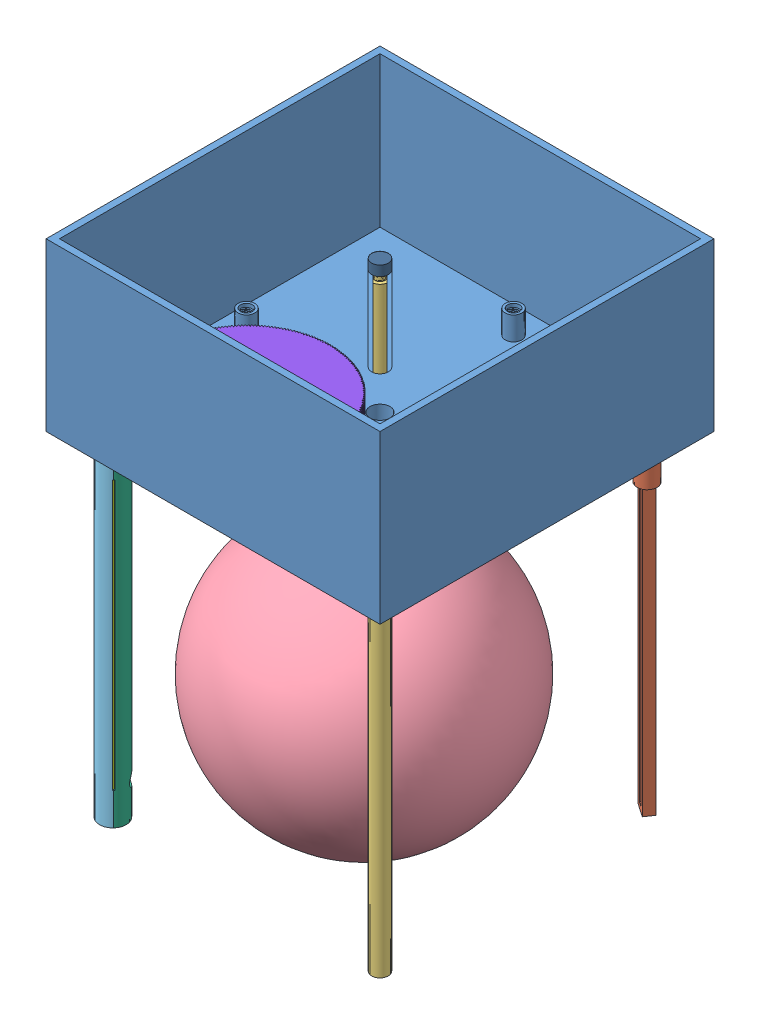
SolidWorks assembly Taşıyıcı kuşak, configuration Varsayılan. Lengths in mm.
Overall size (102.12 154.23 102.12).
15 component instances, 11 part files, 26 mates.
Components (placement in the parent):
- gövde-1: gövde [Varsayılan] at (-14.3626 -37.2025 100) size (100 50 100)
- kuşak desteği-1: kuşak desteği [Varsayılan] at (26.8448 -135.2025 62.6537) x (-0.823429 0 -0.56742) z (0.56742 0 -0.823429) size (6 100 6)
- yardımcı ayak-1: yardımcı ayak [Varsayılan] at (-55.6722 -137.2025 57.9647) x (0.546904 0 0.837196) z (-0.837196 0 0.546904) size (5 102 5)
- yardımcı ayak-2: yardımcı ayak [Varsayılan] at (23.2198 -137.2025 140.7026) x (0.956564 0 -0.291524) z (0.291524 0 0.956564) size (5 102 5)
- drone küresi-1: drone küresi [Varsayılan] at (-18.2063 -101.4294 100.9507) size (80 80 80)
- Montaj2 kusak sıkıştırıcısı-1: Montaj2 kusak sıkıştırıcısı [Varsayılan] at (-90.3425 -98.3272 238.512) x (0.733876 0 0.679283) z (-0.679283 0 0.733876) size (8 103 8)
  - kuşak sıkıştırıcısı 1.yarı-1: kuşak sıkıştırıcısı 1.yarı [Default] at (-40.5128 -38.8753 -96.7362) size (8 103 6)
  - kuşak sıkıştırıcısı 2.yarı-1: kuşak sıkıştırıcısı 2.yarı [Default] at (-40.5128 -38.8753 -96.7362) size (8 103 4)
  - kuşak tutucu-1: kuşak tutucu [Varsayılan] at (-37.5128 -30.8753 -96.7362) x (-0.818094 0 0.575085) z (-0.575085 0 -0.818094) size (1 84 1)
  - kuşak tutucu-2: kuşak tutucu [Varsayılan] at (-43.5128 -30.8753 -96.7362) x (0.97773 0 0.209869) z (-0.209869 0 0.97773) size (1 84 1)
- tetikleyici dişli-1: tetikleyici dişli [Varsayılan] at (-34.2101 -32.2025 119.8475) x (0.932244 0 0.36183) z (-0.36183 0 0.932244) size (49.88 5 49.88)
- tutucu civatası-1: tutucu civatası [Varsayılan] at (-54.3626 -32.2025 140) x (0.951302 0 0.30826) z (-0.30826 0 0.951302) size (7 15.23 6.99)
- yardımcı ayak civatası-1: yardımcı ayak civatası [Varsayılan] at (-54.3049 -32.2025 60.0577) x (-0.034485 0 -0.999405) z (-0.999405 0 0.034485) size (5 8.18 5)
- yardımcı ayak civatası-2: yardımcı ayak civatası [Varsayılan] at (25.6112 -32.2025 139.9738) x (0.995898 0 -0.090486) z (-0.090486 0 -0.995898) size (5 8.18 5)
- kuşak destegi civatası-1: kuşak destegi civatası [Varsayılan] at (25.6374 -32.2025 60) x (-0.844828 0 0.535038) z (0.535038 0 0.844828) size (9.99 17.36 8.86)
Mates (geometry in assembly coordinates):
- Teğet1: tangent anti-aligned: plane of gövde-1 through (-13.3019 -35.2025 98.9393) normal (-0.707107 0 0.707107); cylinder of yardımcı ayak-1 through (-54.3049 -145.7321 60.0577) axis (0 -1 0) radius 1.5
- Çakışık1: coincident aligned: plane of gövde-1 through (-14.3626 -35.2025 100) normal (0 1 0); plane of yardımcı ayak-1 through (-55.1253 -35.2025 58.8019) normal (0 1 0)
- Çakışık2: coincident aligned: plane of gövde-1 through (-14.3626 -35.2025 100) normal (0 1 0); plane of yardımcı ayak-2 through (24.1763 -35.2025 140.4111) normal (0 1 0)
- Teğet4: tangent anti-aligned: plane of gövde-1 through (-15.4233 -35.2025 101.0607) normal (0.707107 0 -0.707107); cylinder of yardımcı ayak-2 through (25.6112 -145.7321 139.9738) axis (0 -1 0) radius 1.5
- Çakışık6: coincident aligned: plane of gövde-1 through (-14.3626 -35.2025 100) normal (0 1 0); plane of kuşak desteği-1 through (25.6374 -35.2025 60) normal (0 1 0)
- Çakışık7: coincident aligned: circle of gövde-1; circle of kuşak desteği-1
- Uzaklığı Sınırla7: limit distance = 36.9629 mm: cylinder of yardımcı ayak-2 through (25.6112 -145.7321 139.9738) axis (0 -1 0) radius 1.5; cylinder of gövde-1 through (-2.6469 -35.2025 111.7157) axis (0 -1 0) radius 1.5
- Uzaklığı Sınırla4: limit distance = 0.0371 mm: cylinder of yardımcı ayak-2 through (25.6112 -145.7321 139.9738) axis (0 -1 0) radius 1.5; cylinder of gövde-1 through (25.6374 -35.2025 140) axis (0 -1 0) radius 1.5
- Uzaklığı Sınırla5: limit distance = 0.0816 mm: cylinder of yardımcı ayak-1 through (-54.3049 -145.7321 60.0577) axis (0 -1 0) radius 1.5; cylinder of gövde-1 through (-54.3626 -35.2025 60) axis (0 -1 0) radius 1.5
- Uzaklığı Sınırla6: limit distance = 36.9184 mm: cylinder of yardımcı ayak-1 through (-54.3049 -145.7321 60.0577) axis (0 -1 0) radius 1.5; cylinder of gövde-1 through (-26.0783 -35.2025 88.2843) axis (0 -1 0) radius 1.5
- Eş Merkezli1: concentric aligned: cylinder of gövde-1 through (-54.3626 -35.2025 140) axis (0 -1 0) radius 3; cylinder of Montaj2 kusak sıkıştırıcısı-1/kuşak sıkıştırıcısı 1.yarı-1 through (-54.3626 -34.2025 140) axis (0 -1 0) radius 3
- Çakışık8: coincident anti-aligned: plane of gövde-1 through (-14.3626 -37.2025 100) normal (0 -1 0); plane of Montaj2 kusak sıkıştırıcısı-1/kuşak sıkıştırıcısı 1.yarı-1 through (-54.3626 -37.2025 140) normal (0 1 0)
- Çakışık9: coincident anti-aligned: plane of gövde-1 through (-14.3626 -32.2025 100) normal (0 1 0); plane of tetikleyici dişli-1 through (-34.2101 -32.2025 119.8475) normal (0 -1 0)
- Eş Merkezli4: concentric aligned: cylinder of gövde-1 through (-54.3626 -34.2025 140) axis (0 1 0) radius 2.5; cylinder of tutucu civatası-1 through (-54.3626 -42.2025 140) axis (0 1 0) radius 2.5
- Kilitle1: lock: unknown of Montaj2 kusak sıkıştırıcısı-1/kuşak sıkıştırıcısı 2.yarı-1; unknown of tutucu civatası-1
- GearMate1: gear = 1 : 1 mm: line of tutucu civatası-1 through (-54.7099 -27.2025 142.9798) axis (-0.571188 0 0.82082); line of tetikleyici dişli-1 through (-12.501 -27.2025 107.5663) axis (-0.571188 0 0.82082)
- Eş Merkezli5: concentric aligned: circle of yardımcı ayak-2; circle of yardımcı ayak civatası-2
- Çakışık10: coincident anti-aligned: plane of yardımcı ayak-2 through (25.6112 -40.2025 139.9738) normal (0 1 0); plane of yardımcı ayak civatası-2 through (25.6112 -40.2025 139.9738) normal (0 -1 0)
- Kilitle2: lock: unknown of yardımcı ayak-2; unknown of yardımcı ayak civatası-2
- Eş Merkezli6: concentric aligned: circle of yardımcı ayak-1; circle of yardımcı ayak civatası-1
- Çakışık11: coincident anti-aligned: plane of yardımcı ayak-1 through (-54.3049 -40.2025 60.0577) normal (0 1 0); plane of yardımcı ayak civatası-1 through (-54.3049 -40.2025 60.0577) normal (0 -1 0)
- Kilitle3: lock: unknown of yardımcı ayak-1; unknown of yardımcı ayak civatası-1
- Çakışık12: coincident anti-aligned: cylinder of gövde-1 through (-34.2101 -27.2025 119.8475) axis (0 -1 0) radius 2.5; circle of tetikleyici dişli-1
- Eş Merkezli7: concentric anti-aligned: circle of kuşak desteği-1; circle of kuşak destegi civatası-1
- Çakışık15: coincident anti-aligned: line of gövde-1 through (29.9675 -32.2025 62.5) axis (0 0 -1); line of kuşak destegi civatası-1 through (29.9675 -32.2025 57.5) axis (0 0 1)
- Kilitle4: lock: unknown of kuşak desteği-1; unknown of kuşak destegi civatası-1
